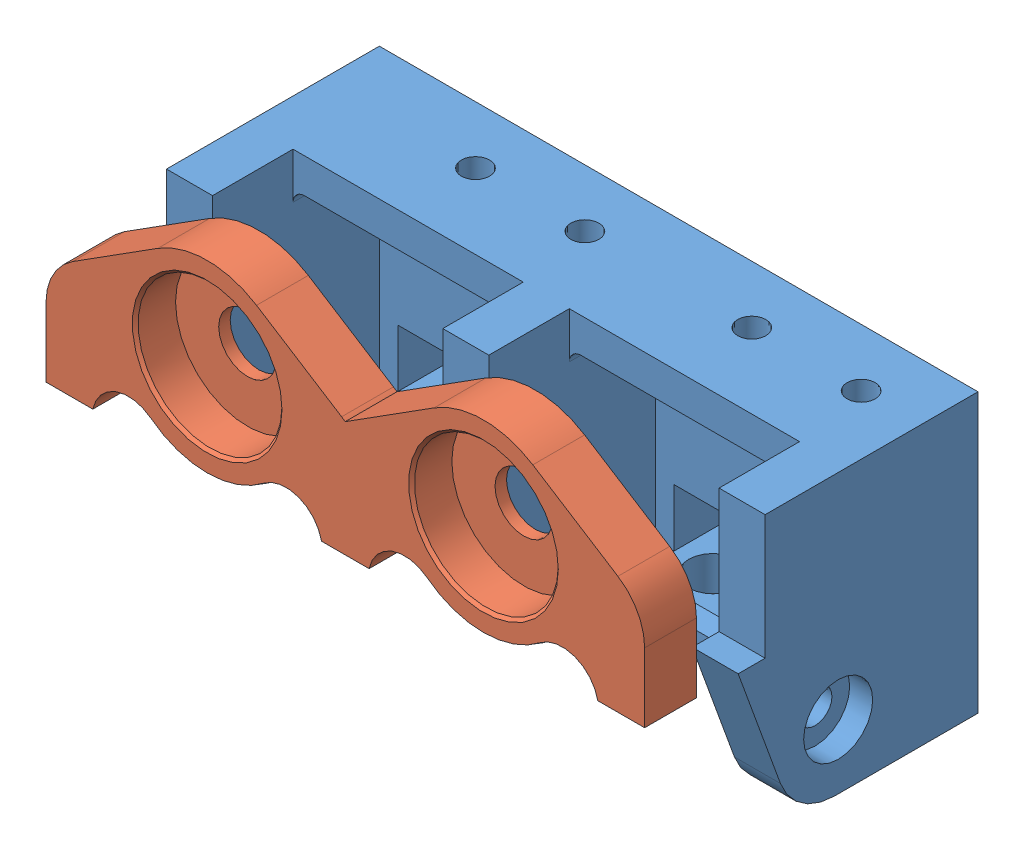
SolidWorks assembly base RJ, configuration Default. Lengths in mm.
Overall size (52 29.55 28.96).
2 component instances, 2 part files, 4 mates.
Components (placement in the parent):
- double main body base chop-1: double main body base chop [Default] at (-1.892 -0.6688 -5.1295) size (52 24.18 20.83)
- double main body magnet chop-1: double main body magnet chop [Default] at (-1.892 -20.664 -3.6733) size (52 16.17 4.5)
Mates (geometry in assembly coordinates):
- Coincident1: coincident aligned: plane of double main body base chop-1 through (44.454 36.8031 44.0217) normal (1 0 0); plane of double main body magnet chop-1 through (44.454 16.8078 45.4779) normal (1 0 0)
- Parallel4: parallel aligned: plane of double main body base chop-1 through (20.454 26.1811 30.0217) normal (0 0 -1); plane of double main body magnet chop-1 through (6.454 31.8046 54.4779) normal (0 0 -1)
- Distance3: distance = 15.35 mm: cylinder of double main body base chop-1 through (46.9795 17.7264 42.1679) axis (-1 0 0) radius 1.46; plane of double main body magnet chop-1 through (20.454 33.6779 58.9779) normal (0 0 1)
- Distance5: distance = 5.37 mm: point of double main body base chop-1; moEndPointRef_w of double main body magnet chop-1
